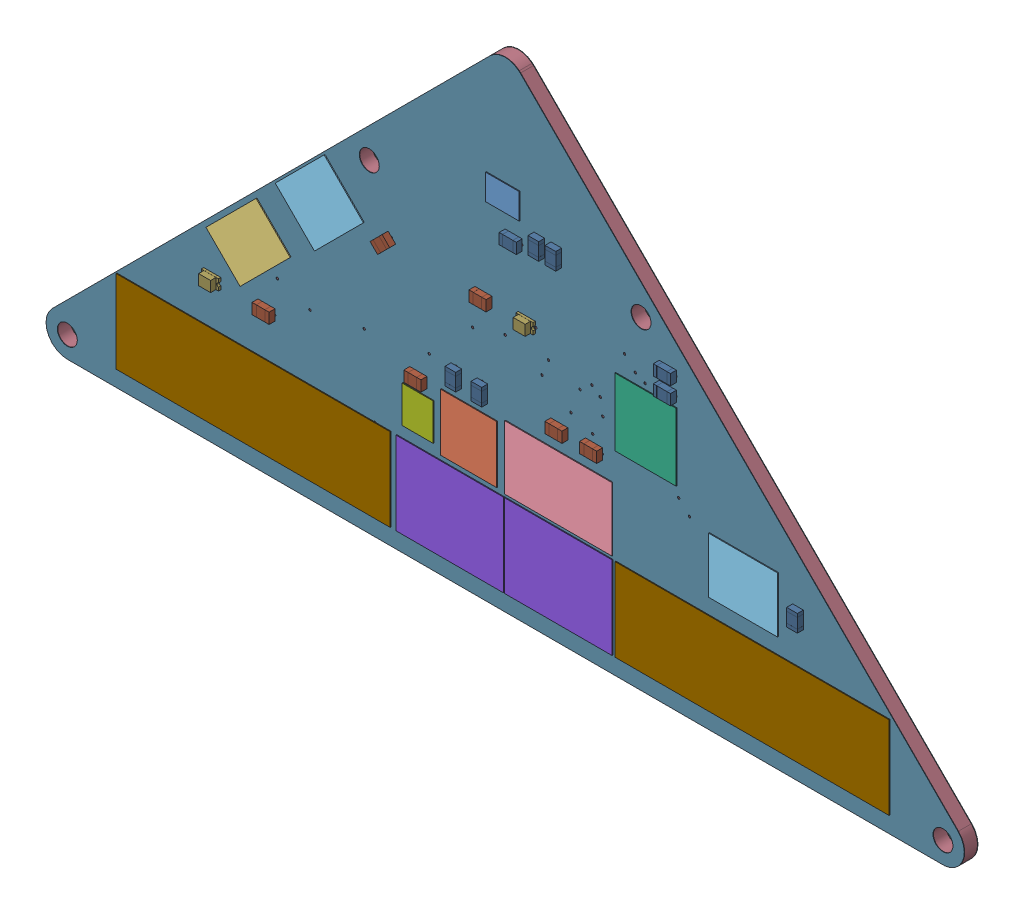
SolidWorks assembly pcb v8.step, configuration Default. Lengths in mm.
Overall size (107.52 56.26 2.5).
32 component instances, 15 part files, 0 mates.
Components (placement in the parent):
- Packages.step-1: Packages.step [Default] at origin size (90.52 41.61 0.9)
  - PQFN50P300X250X97-14N.step-1: PQFN50P300X250X97-14N.step [Default] at (0 -15.24 1.5525) size (3.95 2.99 0.1)
  - AP220533YR13.step-1: AP220533YR13.step [Default] at (-4.191 -41.275 1.5525) x (-1 0 0) z (0 0 1) size (6.6 6.7 0.1)
  - CUS-12B.step-1: CUS-12B.step [Default] at (-30.48 -34.29 1.5525) x (-0.707107 -0.707107 0) z (0 0 1) size (8.3 5.65 0.1)
  - OS102011MS2QS1.step-1: OS102011MS2QS1.step [Default] at (4.318 -41.021 1.5525) size (12.55 7.45 0.1)
  - PTS526SM15SMTR2LFS.step-1: PTS526SM15SMTR2LFS.step [Default] at (27.94 -40.64 1.5525) size (8.1 6.5 0.1)
  - PTS526SM15SMTR2LFS.step-2: PTS526SM15SMTR2LFS.step [Default] at (-21.59 -26.67 1.5525) x (0.707107 0.707107 0) z (0 0 1) size (8.1 6.5 0.1)
  - SOP65P640X120-20N.step-1: SOP65P640X120-20N.step [Default] at (16.51 -30.48 1.5525) x (0 -1 0) z (0 0 1) size (7.9 7.17 0.1)
  - SOT95P285X140-3N.step-1: SOT95P285X140-3N.step [Default] at (-10.16 -42.164 1.5525) x (0 -1 0) z (0 0 1) size (4.3 3.65 0.1)
  - TB00250002BE.step-1: TB00250002BE.step [Default] at (-8.89 -50.8 1.5525) size (12.6 9.7 0.1)
  - TB00250002BE.step-2: TB00250002BE.step [Default] at (3.81 -50.8 1.5525) size (12.6 9.7 0.1)
  - TB00250006BE.step-1: TB00250006BE.step [Default] at (-41.91 -50.8 1.5525) size (32.1 9.7 0.1)
  - TB00250006BE.step-2: TB00250006BE.step [Default] at (16.51 -50.8 1.5525) size (32.1 9.7 0.1)
  - C0805.step-1: C0805.step [Default] at (34.29 -40.64 1.5525) x (0 -1 0) z (0 0 1) size (2 1.25 0.7)
  - C0805.step-2: C0805.step [Default] at (19.05 -25.4 1.5525) size (2 1.25 0.7)
  - C0805.step-3: C0805.step [Default] at (6 -18.08 1.5525) x (0 -1 0) z (0 0 1) size (2 1.25 0.7)
  - C0805.step-4: C0805.step [Default] at (-2.667 -36.195 1.5525) x (0 1 0) z (0 0 1) size (2 1.25 0.7)
  - C0805.step-5: C0805.step [Default] at (19.05 -23.368 1.5525) size (2 1.25 0.7)
  - C0805.step-6: C0805.step [Default] at (4 -18.08 1.5525) x (0 -1 0) z (0 0 1) size (2 1.25 0.7)
  - C0805.step-7: C0805.step [Default] at (-5.715 -36.195 1.5525) x (0 1 0) z (0 0 1) size (2 1.25 0.7)
  - C0805.step-8: C0805.step [Default] at (1 -19.08 1.5525) size (2 1.25 0.7)
  - R0805.step-1: R0805.step [Default] at (-10.16 -38.608 1.5525) x (-1 0 0) z (0 0 1) size (2 1.25 0.7)
  - R0805.step-2: R0805.step [Default] at (-13.97 -26.67 1.5525) x (0.707107 0.707107 0) z (0 0 1) size (2 1.25 0.7)
  - R0805.step-3: R0805.step [Default] at (6.35 -35.56 1.5525) x (-1 0 0) z (0 0 1) size (2 1.25 0.7)
  - R0805.step-4: R0805.step [Default] at (10.414 -35.56 1.5525) x (-1 0 0) z (0 0 1) size (2 1.25 0.7)
  - R0805.step-5: R0805.step [Default] at (-2.54 -26.67 1.5525) x (-1 0 0) z (0 0 1) size (2 1.25 0.7)
  - R0805.step-6: R0805.step [Default] at (-27.94 -40.64 1.5525) size (2 1.25 0.7)
  - CHIP-LED0805.step-1: CHIP-LED0805.step [Default] at (2.54 -26.67 1.5525) x (0 1 0) z (0 0 1) size (1.25 2 0.9)
  - CHIP-LED0805.step-2: CHIP-LED0805.step [Default] at (-34.29 -40.64 1.5525) x (0 -1 0) z (0 0 1) size (1.25 2 0.9)
- Board.step-1: Board.step [Default] at origin size (107.52 56.26 1.5)
- 1-soldermask.step-1: 1-soldermask.step [Default] at (0 0 1.5) size (107.52 56.26 0.05)
- 16-soldermask.step-1: 16-soldermask.step [Default] at origin size (107.52 56.26 0.05)
